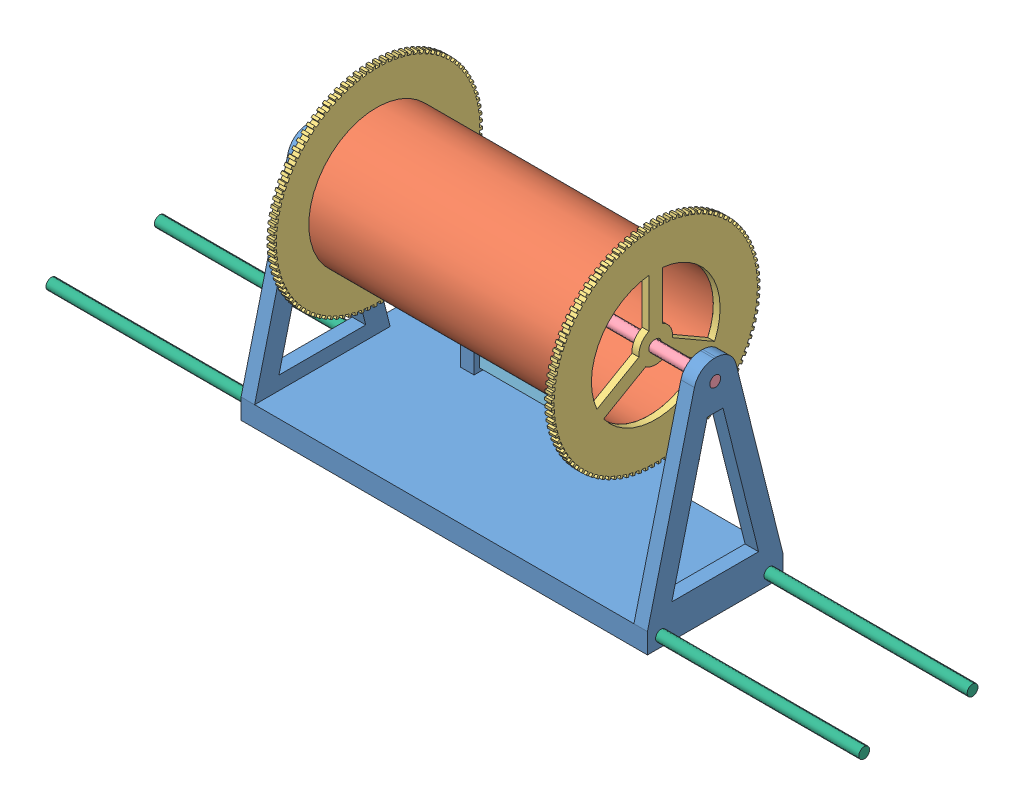
SolidWorks assembly drum_carrier_assembly, configuration Default. Lengths in mm.
Overall size (600 227 175.88).
9 component instances, 6 part files, 8 mates.
Components (placement in the parent):
- drum_carrier-1: drum_carrier [Default] at origin size (300 165 150)
- drumroll_assembly_V2-1: drumroll_assembly_V2 [Default] at (0 150 0) size (300 154.01 154.01)
  - drumroll_V2-1: drumroll_V2 [Default] at origin size (200 100 100)
  - drumroll_V2_end-2: drumroll_V2_end [Default] at (100 0 -1.1204) size (5 154.01 154.01)
  - drumroll_V2_end-3: drumroll_V2_end [Default] at (-105 0 -1.1204) size (5 154.01 154.01)
  - drum_smooth_rod-1: drum_smooth_rod [Default] at origin size (300 8 8)
- Nema17motor-1: Nema17motor [Default] at (-78 38.8897 -75) size (76 42.3 42.3)
- drum_carrier_rod-1: drum_carrier_rod [Default] at (0 7.5 -40) size (600 8 8)
- drum_carrier_rod-2: drum_carrier_rod [Default] at (0 7.5 40) size (600 8 8)
Mates (geometry in assembly coordinates):
- Coincident2: coincident aligned: plane of drumroll_assembly_V2-1/drumroll_V2-1 through (0 150 0) normal (1 0 0); plane of assembly through (0 0 0) normal (1 0 0)
- Coincident3: coincident anti-aligned: line of drum_carrier-1 through (140 150 0) axis (1 0 0); line of drumroll_assembly_V2-1/drumroll_V2-1 through (110 150 0) axis (-1 0 0)
- Concentric2: concentric aligned: cylinder of drum_carrier-1 through (-78 22.3897 -90.5) axis (-1 0 0) radius 2; cylinder of Nema17motor-1 through (-73.5 22.3897 -90.5) axis (-1 0 0) radius 2
- Coincident4: coincident anti-aligned: plane of drum_carrier-1 through (-78 65 -50) normal (1 0 0); plane of Nema17motor-1 through (-78 38.8897 -75) normal (-1 0 0)
- Coincident5: coincident: line of drum_carrier-1 through (-150 7.5 -40) axis (1 0 0); line of drum_carrier_rod-1 through (-157.7239 7.5 -40) axis (-1 0 0)
- Coincident6: coincident aligned: plane of drum_carrier-1 through (0 0 0) normal (1 0 0); plane of drum_carrier_rod-1 through (0 7.5 -40) normal (1 0 0)
- Coincident7: coincident: plane of drum_carrier-1 through (0 0 0) normal (1 0 0); plane of drum_carrier_rod-2 through (0 7.5 40) normal (1 0 0)
- Coincident8: coincident anti-aligned: line of drum_carrier-1 through (-150 7.5 40) axis (1 0 0); line of drum_carrier_rod-2 through (300 7.5 40) axis (-1 0 0)
